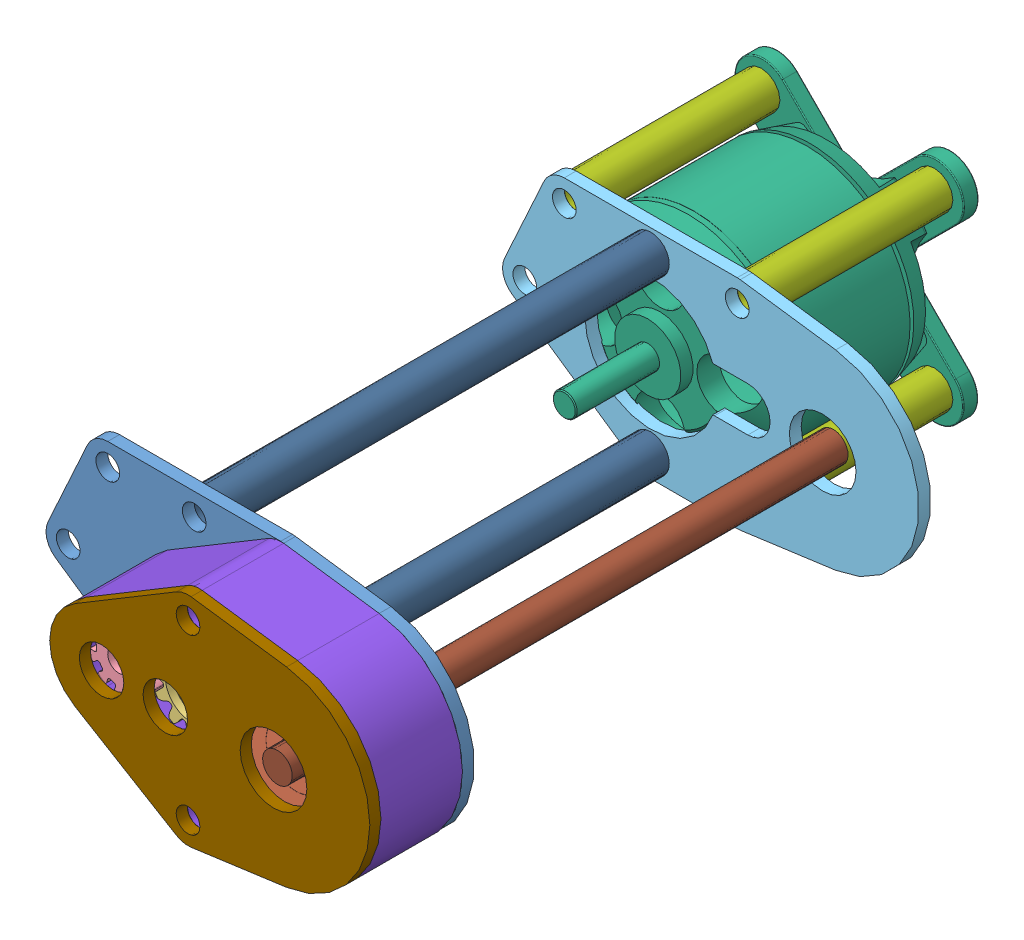
SolidWorks assembly Mini Dribbler Assembly, configuration Default. Lengths in mm.
Overall size (63.68 55.25 102.7).
14 component instances, 11 part files, 25 mates.
Components (placement in the parent):
- Mini Dribbler Plate 1-1: Mini Dribbler Plate 1 [Default] at (17.6819 30.615 43.728) size (56.2 29.33 1.6)
- front - Gear-1: front - Gear [Default] at (40.8819 30.615 53.328) x (0 0 -1) z (0 -1 0) size (9.5 21.56 21.6)
- mid-gear-1: mid-gear [Default] at (26.2819 30.615 52.328) x (0 0 -1) z (1 0 0) size (9 11.2 11.2)
- BrushlessGear-1: BrushlessGear [Default] at (17.6819 30.615 50.498) x (0 0 -1) z (0.318408 -0.947954 0) size (10.17 9.6 9.6)
- Mini Dribbler Plate3-1: Mini Dribbler Plate3 [Default] at (17.6819 30.615 -17.872) size (56.2 29.33 1.6)
- Stand-1: Stand [Default] at (-21.2758 41.2029 -36.4834) x (0.835959 -0.548791 0) z (0.548791 0.835959 0) size (39.9 40.4 39.9)
- 25mm - pole-1: 25mm - pole [Default] at (29.3492 18.9478 -42.872) size (5 5 25)
- 25mm - pole-2: 25mm - pole [Default] at (29.3492 42.2823 -42.872) size (5 5 25)
- 25mm - pole-3: 25mm - pole [Default] at (6.0146 42.2823 -42.872) size (5 5 25)
- Mini Dribbler wall-1: Mini Dribbler wall [Default] at (17.6819 30.615 42.228) size (43.2 29.33 11)
- Mini Dribbler Plate 2-2: Mini Dribbler Plate 2 [Default] at (17.6819 30.615 54.728) size (43.2 29.33 1.5)
- 60mm - pole-3: 60mm - pole [Default] at (17.6819 18.9478 -16.272) size (5 5 60)
- 60mm - pole-4: 60mm - pole [Default] at (17.6819 42.2823 -16.272) size (5 5 60)
- Rod-1: Rod [Default] at (40.8819 30.615 -17.6993) x (-0.550731 -0.834683 0) z (-0.834683 0.550731 0) size (4 75 4)
Mates (geometry in assembly coordinates):
- Coincident14: coincident anti-aligned: plane of Mini Dribbler Plate 1-1 through (29.3492 42.2823 45.328) normal (0 0 1); plane of BrushlessGear-1 through (17.6819 30.615 45.328) normal (0 0 -1)
- Coincident15: coincident anti-aligned: plane of Mini Dribbler Plate 1-1 through (29.3492 42.2823 45.328) normal (0 0 1); plane of mid-gear-1 through (26.2819 30.615 45.328) normal (0 0 -1)
- Coincident16: coincident anti-aligned: plane of Mini Dribbler Plate 1-1 through (29.3492 42.2823 45.328) normal (0 0 1); plane of front - Gear-1 through (40.8819 30.615 45.328) normal (0 0 -1)
- Coincident39: coincident anti-aligned: plane of Mini Dribbler Plate3-1 through (29.3492 42.2823 -17.872) normal (0 0 -1); plane of 25mm - pole-3 through (6.0146 42.2823 -17.872) normal (0 0 1)
- Concentric47: concentric aligned: cylinder of Mini Dribbler Plate3-1 through (6.0146 42.2823 -16.272) axis (0 0 -1) radius 1.6; cylinder of 25mm - pole-3 through (6.0146 42.2823 -17.872) axis (0 0 -1) radius 1.6
- Coincident40: coincident anti-aligned: plane of Mini Dribbler Plate3-1 through (29.3492 42.2823 -17.872) normal (0 0 -1); plane of 25mm - pole-2 through (29.3492 42.2823 -17.872) normal (0 0 1)
- Concentric48: concentric aligned: cylinder of Mini Dribbler Plate3-1 through (29.3492 42.2823 -16.272) axis (0 0 -1) radius 1.6; cylinder of 25mm - pole-2 through (29.3492 42.2823 -17.872) axis (0 0 -1) radius 1.6
- Coincident41: coincident anti-aligned: plane of Mini Dribbler Plate3-1 through (29.3492 42.2823 -17.872) normal (0 0 -1); plane of 25mm - pole-1 through (29.3492 18.9478 -17.872) normal (0 0 1)
- Concentric49: concentric aligned: cylinder of Mini Dribbler Plate3-1 through (29.3492 18.9478 -16.272) axis (0 0 -1) radius 1.6; cylinder of 25mm - pole-1 through (29.3492 18.9478 -17.872) axis (0 0 -1) radius 1.6
- Coincident42: coincident anti-aligned: plane of Stand-1 through (29.4638 18.8326 -42.872) normal (0 0 1); plane of 25mm - pole-1 through (29.3492 18.9478 -42.872) normal (0 0 -1)
- Concentric50: concentric aligned: cylinder of Mini Dribbler Plate 1-1 through (29.3492 18.9478 45.328) axis (0 0 -1) radius 1.6; cylinder of Mini Dribbler wall-1 through (29.3492 18.9478 43.828) axis (0 0 -1) radius 1.6
- Concentric51: concentric aligned: cylinder of Mini Dribbler Plate 1-1 through (29.3492 42.2823 45.328) axis (0 0 -1) radius 1.6; cylinder of Mini Dribbler wall-1 through (29.3492 42.2823 43.828) axis (0 0 -1) radius 1.6
- Coincident43: coincident anti-aligned: plane of Mini Dribbler Plate 1-1 through (29.3492 42.2823 45.328) normal (0 0 1); plane of Mini Dribbler wall-1 through (29.3492 42.2823 45.328) normal (0 0 -1)
- Coincident44: coincident anti-aligned: plane of Mini Dribbler wall-1 through (17.6819 30.615 56.328) normal (0 0 1); plane of Mini Dribbler Plate 2-2 through (17.6819 30.615 56.328) normal (0 0 -1)
- Concentric52: concentric aligned: cylinder of Mini Dribbler wall-1 through (29.3492 18.9478 43.828) axis (0 0 -1) radius 1.6; cylinder of Mini Dribbler Plate 2-2 through (29.3492 18.9478 56.328) axis (0 0 -1) radius 1.6
- Concentric53: concentric aligned: cylinder of Mini Dribbler wall-1 through (29.3492 42.2823 43.828) axis (0 0 -1) radius 1.6; cylinder of Mini Dribbler Plate 2-2 through (29.3492 42.2823 56.328) axis (0 0 -1) radius 1.6
- Coincident45: coincident anti-aligned: plane of Mini Dribbler Plate3-1 through (29.3492 42.2823 -16.272) normal (0 0 1); plane of 60mm - pole-4 through (17.6819 42.2823 -16.272) normal (0 0 -1)
- Concentric54: concentric aligned: cylinder of Mini Dribbler Plate3-1 through (17.6819 42.2823 -16.272) axis (0 0 -1) radius 1.6; cylinder of 60mm - pole-4 through (17.6819 42.2823 43.728) axis (0 0 -1) radius 1.6
- Coincident46: coincident anti-aligned: plane of Mini Dribbler Plate3-1 through (29.3492 42.2823 -16.272) normal (0 0 1); plane of 60mm - pole-3 through (17.6819 18.9478 -16.272) normal (0 0 -1)
- Concentric55: concentric aligned: cylinder of Mini Dribbler Plate3-1 through (17.6819 18.9478 -16.272) axis (0 0 -1) radius 1.6; cylinder of 60mm - pole-3 through (17.6819 18.9478 43.728) axis (0 0 -1) radius 1.6
- Coincident47: coincident anti-aligned: plane of Mini Dribbler Plate 1-1 through (29.3492 42.2823 43.728) normal (0 0 -1); plane of 60mm - pole-3 through (17.6819 18.9478 43.728) normal (0 0 1)
- Concentric56: concentric aligned: cylinder of Mini Dribbler Plate 1-1 through (17.6819 18.9478 45.328) axis (0 0 -1) radius 1.6; cylinder of 60mm - pole-3 through (17.6819 18.9478 43.728) axis (0 0 -1) radius 1.6
- Concentric57: concentric aligned: cylinder of Mini Dribbler Plate 1-1 through (17.6819 42.2823 45.328) axis (0 0 -1) radius 1.6; cylinder of 60mm - pole-4 through (17.6819 42.2823 43.728) axis (0 0 -1) radius 1.6
- Concentric61: concentric aligned: cylinder of Mini Dribbler Plate 1-1 through (0.6819 30.615 45.328) axis (0 0 -1) radius 1.6; cylinder of Mini Dribbler Plate3-1 through (0.6819 30.615 -16.272) axis (0 0 -1) radius 1.6
- Concentric63: concentric aligned: cylinder of Mini Dribbler Plate3-1 through (40.8819 30.615 -16.272) axis (0 0 -1) radius 4.5; cylinder of Rod-1 through (40.8819 30.615 57.3007) axis (0 0 -1) radius 2
